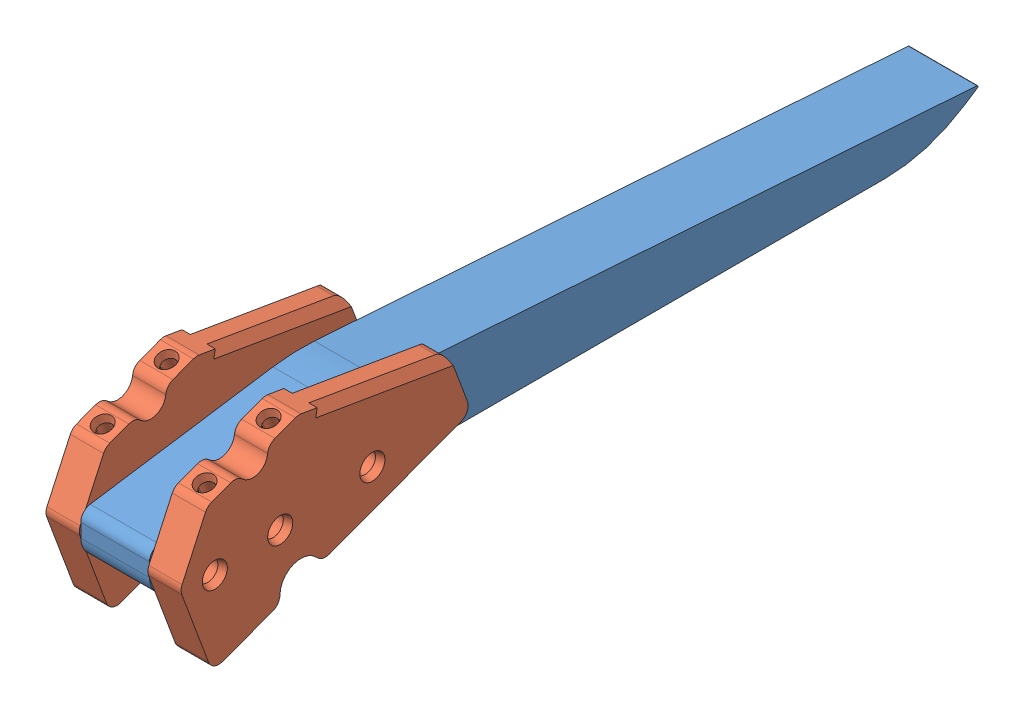
SolidWorks assembly Body, configuration Default. Lengths in mm.
Overall size (30.99 51.83 194.24).
3 component instances, 2 part files, 6 mates.
Components (placement in the parent):
- Tail-1: Tail [Default] at (73.3976 101.4468 142.9508) size (15.75 17.53 189.98)
- Side-1: Side [Default] at (61.7136 98.5617 215.0109) x (-1 0 0) z (0 0.34834 -0.937368) size (7.62 31.75 63.36)
- Side-2: Side [Default] at (85.0816 98.5617 215.0109) x (-1 0 0) z (0 0.34834 -0.937368) size (7.62 31.75 63.36)
Mates (geometry in assembly coordinates):
- Coincident1: coincident anti-aligned: plane of Tail-1 through (81.2716 126.6212 69.5508) normal (1 0 0); plane of Side-2 through (81.2716 117.206 216.1769) normal (-1 0 0)
- Coincident2: coincident anti-aligned: plane of Tail-1 through (65.5236 126.6212 69.5508) normal (-1 0 0); plane of Side-1 through (65.5236 117.206 216.1769) normal (1 0 0)
- Concentric1: concentric anti-aligned: cylinder of Tail-1 through (65.5236 102.7812 194.7121) axis (1 0 0) radius 2.3813; cylinder of Side-1 through (65.5236 102.7812 194.7121) axis (-1 0 0) radius 2.3813
- Concentric2: concentric anti-aligned: cylinder of Tail-1 through (65.5236 102.7812 194.7121) axis (1 0 0) radius 2.3813; cylinder of Side-2 through (88.8916 102.7812 194.7121) axis (-1 0 0) radius 2.3813
- Concentric6: concentric anti-aligned: cylinder of Tail-1 through (65.5236 99.3754 230.8377) axis (1 0 0) radius 2.3813; cylinder of Side-2 through (88.8916 99.3754 230.8377) axis (-1 0 0) radius 2.3813
- Concentric7: concentric anti-aligned: cylinder of Tail-1 through (65.5236 99.3754 230.8377) axis (1 0 0) radius 2.3813; cylinder of Side-1 through (65.5236 99.3754 230.8377) axis (-1 0 0) radius 2.3813
